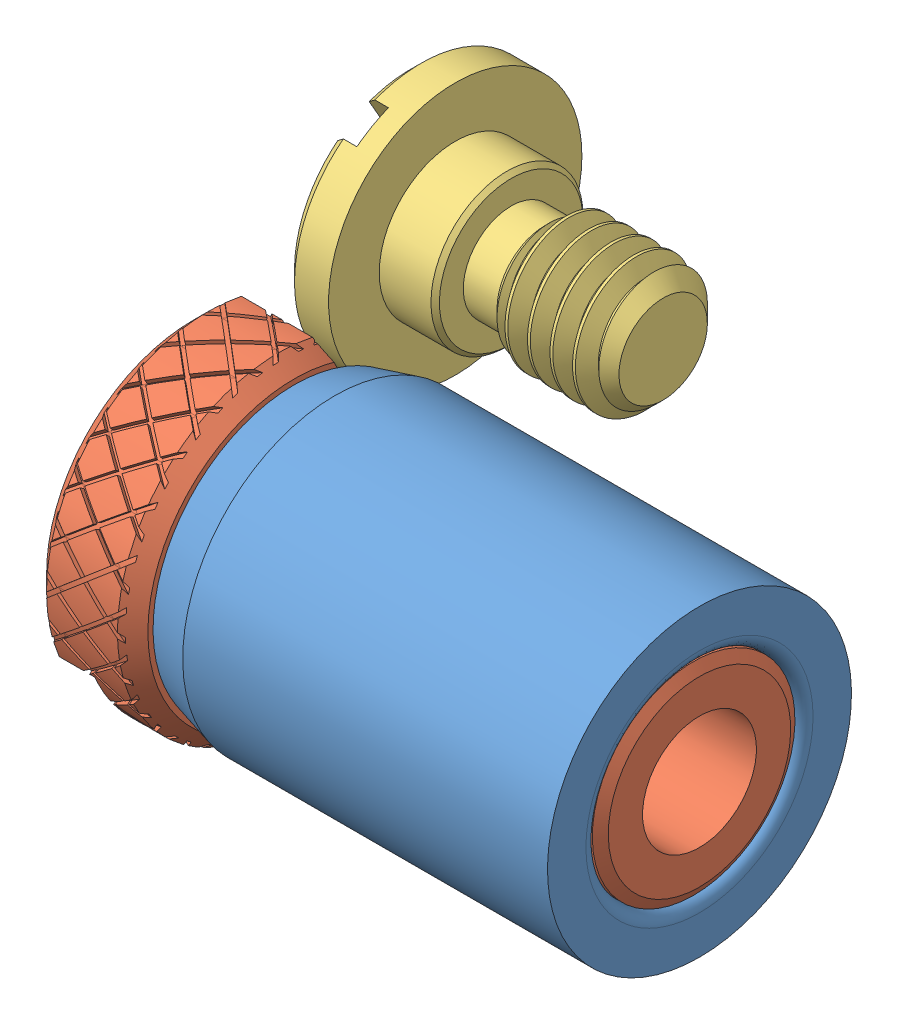
SolidWorks assembly 7 mm Bushing, configuration Default. Lengths in mm.
Overall size (31.75 37.33 35.17).
3 component instances, 3 part files, 4 mates.
Components (placement in the parent):
- 3556N159_Sleeve for Removable Drill Bushing-1: 3556N159_Sleeve for Removable Drill Bushing [3556N159] at (-0.0394 16.7346 22.1566)
- 8493A169_Removable Drill Bushing-1: 8493A169_Removable Drill Bushing [8493A169] at (-3.2144 16.7346 22.1566) x (1 0 0) z (0 0.635804 0.771851)
- 8496A13_Lock Screw for Removable Drill Bushings-1: 8496A13_Lock Screw for Removable Drill Bushings [8496A13] at (-7.6467 28.9877 12.0632) x (1 0 0) z (0 -0.868859 -0.495059)
Mates (geometry in assembly coordinates):
- Concentric1: concentric aligned: cylinder of 3556N159_Sleeve for Removable Drill Bushing-1 through (-12.7394 16.7346 22.1566) axis (-1 0 0) radius 9.525; cylinder of 8493A169_Removable Drill Bushing-1 through (-19.0894 16.7346 22.1566) axis (-1 0 0) radius 6.35
- Coincident1: coincident anti-aligned: plane of 3556N159_Sleeve for Removable Drill Bushing-1 through (-12.7394 25.579 22.1566) normal (-1 0 0); plane of 8493A169_Removable Drill Bushing-1 through (-12.7394 24.5459 15.7221) normal (1 0 0)
- Concentric2: concentric anti-aligned: cylinder of 8493A169_Removable Drill Bushing-1 through (10.8338 28.9877 12.0632) axis (-1 0 0) radius 8.3344; cylinder of 8496A13_Lock Screw for Removable Drill Bushings-1 through (-15.5842 28.9877 12.0632) axis (1 0 0) radius 7.9375
- Coincident2: coincident anti-aligned: plane of 3556N159_Sleeve for Removable Drill Bushing-1 through (-12.7394 25.579 22.1566) normal (-1 0 0); plane of 8496A13_Lock Screw for Removable Drill Bushings-1 through (-12.7394 28.9877 12.0632) normal (1 0 0)
